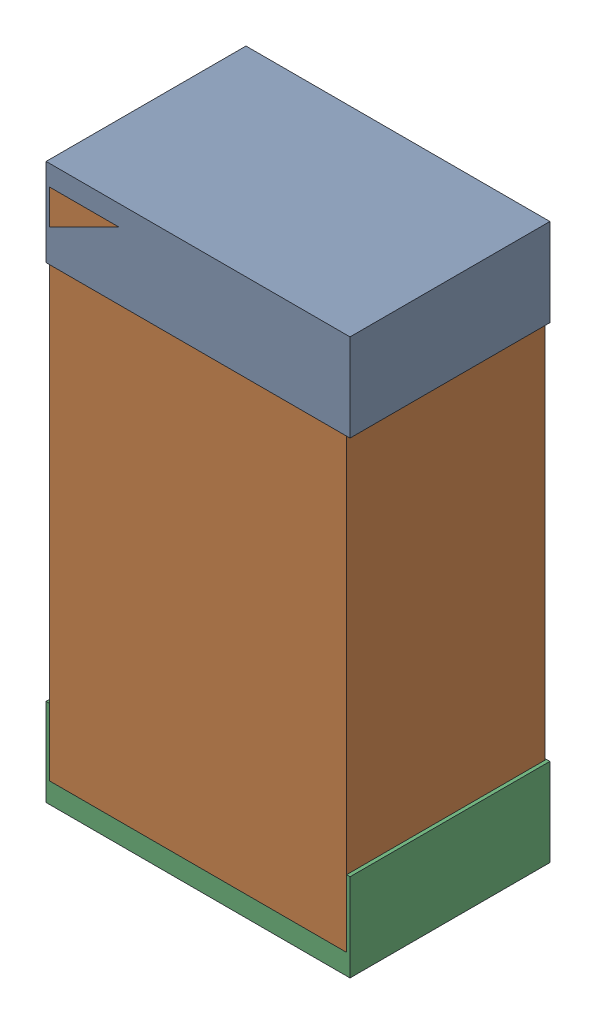
SolidWorks assembly R17Kanaloa_v2.0.0_Motor, configuration Default. Lengths in mm.
Overall size (1.3 2.38 0.85).
6 component instances, 2 part files, 0 mates.
Components (placement in the parent):
- 330415056-1: 330415056 [Default] at (85.09 67.294 -1.9574) size (1.3 0.38 0.85)
  - Extruded_2-1: Extruded_2 [Default] at origin size (1.3 0.38 0.85)
- 334787376-1: 334787376 [Default] at (85.09 66.294 -1.9524) size (1.27 2.2 0.85)
  - Extruded_16-1: Extruded_16 [Default] at origin size (1.27 2.2 0.85)
- 330415056-2: 330415056 [Default] at (85.09 65.294 -1.9574) size (1.3 0.38 0.85)
  - Extruded_2-1: Extruded_2 [Default] at origin size (1.3 0.38 0.85)
